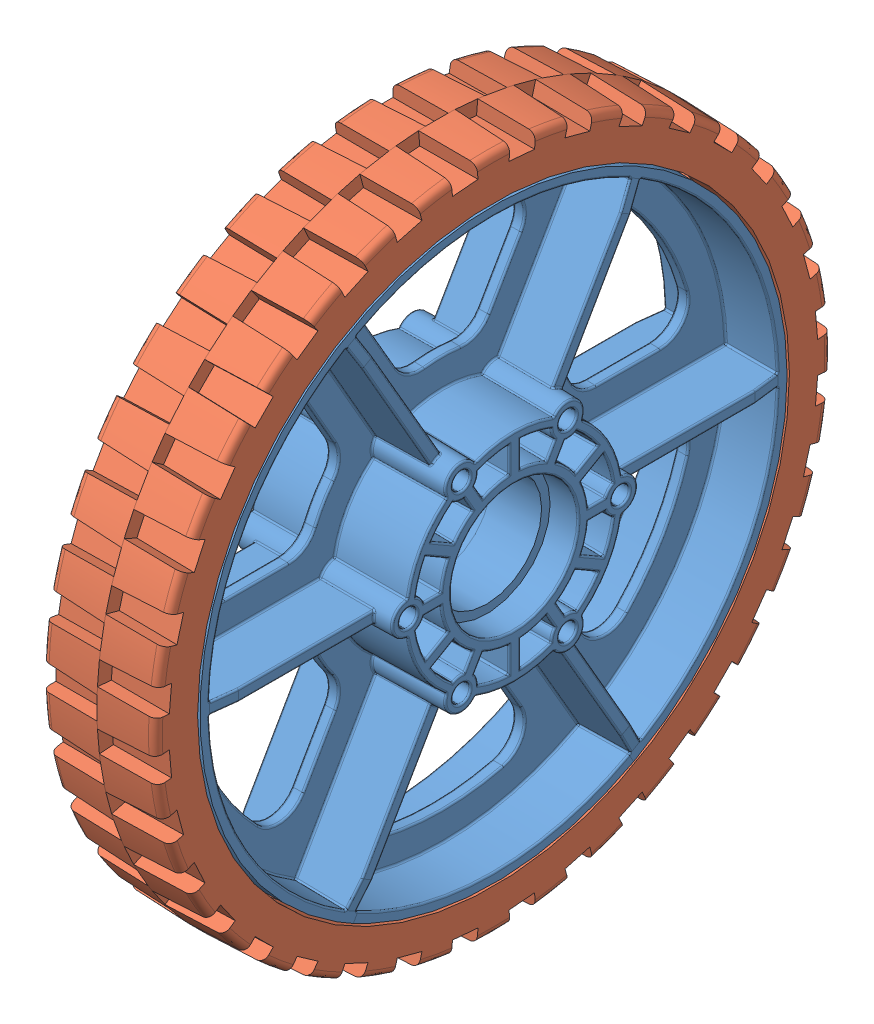
SolidWorks assembly Wheel HiGrip 6 in, configuration Default. Lengths in mm.
Overall size (35.05 152.4 152.4).
2 component instances, 2 part files, 2 mates.
Components (placement in the parent):
- Wheel HiGrip 6 in_Wheel-1: Wheel HiGrip 6 in_Wheel [Default] at (-52.6446 9.4231 21.378) size (35.05 132.08 132.08)
- Wheel HiGrip 6 in_Tread-1: Wheel HiGrip 6 in_Tread [Default] at (-65.3446 9.4231 21.378) x (0 0 -1) z (1 0 0) size (152.4 152.4 25.58)
Mates (geometry in assembly coordinates):
- Concentric1: concentric anti-aligned: circle of Wheel HiGrip 6 in_Wheel-1; circle of Wheel HiGrip 6 in_Tread-1
- Coincident1: coincident aligned: plane of Wheel HiGrip 6 in_Wheel-1 through (-39.9446 9.4231 21.378) normal (1 0 0); plane of Wheel HiGrip 6 in_Tread-1 through (-39.9446 9.4231 87.672) normal (1 0 0)
